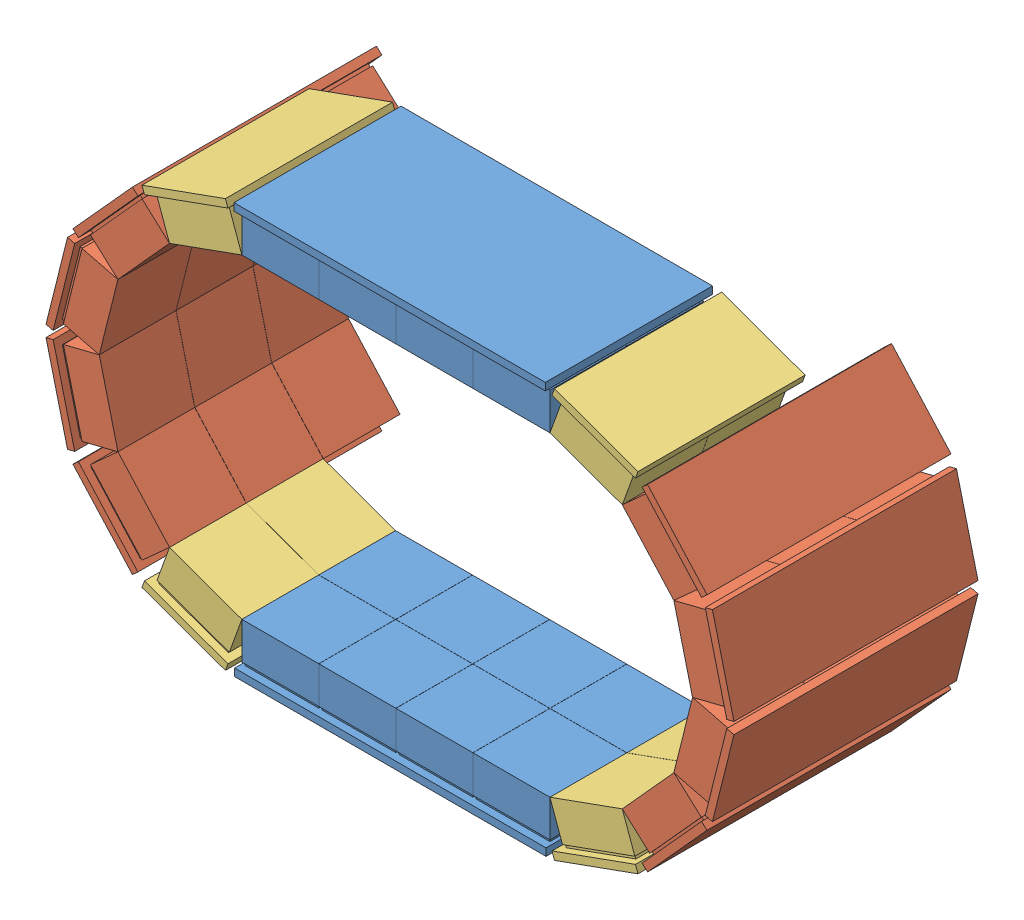
SolidWorks assembly HorseShoes, configuration Default. Lengths in mm.
Overall size (517.67 317.54 165).
16 component instances, 3 part files, 10 mates.
Components (placement in the parent):
- 52mmTOPBOTTOM-1: 52mmTOPBOTTOM [Default] at (-69.8528 -35.4842 8.7442) size (210.55 32 113)
- SideDetector-1: SideDetector [Default] at (215.9367 233.9438 -54.2197) x (-0.242515 0.970148 0) z (0 0 1) size (268 155.36 165)
  - 52mmX4-1: 52mmX4 [Default] at (-99.1405 6.5957 36.9639) size (60 32 165)
  - 52mmX4-2: 52mmX4 [Default] at (-35.1412 22.594 36.9639) x (0.882373 0.47055 0) z (0 0 1) size (60 32 165)
  - 52mmX4-3: 52mmX4 [Default] at (-163.1399 22.594 36.9639) x (0.882373 -0.47055 0) z (0 0 1) size (60 32 165)
  - 52mmX4-4: 52mmX4 [Default] at (-212.0831 66.8254 36.9639) x (0.557166 -0.830401 0) z (0 0 1) size (60 32 165)
  - 52mmX3-1: 52mmX3 [Default] at (-234.4563 128.8843 62.9639) x (0.100883 -0.994898 0) z (0 0 1) size (60 32 113)
  - 52mmX3-2: 52mmX3 [Default] at (13.802 66.8254 62.9639) x (0.557166 0.830401 0) z (0 0 1) size (60 32 113)
- SideDetector-2: SideDetector [Default] at (-199.3424 -27.5859 -54.2197) x (0.242515 -0.970148 0) z (0 0 1) size (268 155.36 165)
  - 52mmX4-1: 52mmX4 [Default] at (-99.1405 6.5957 36.9639) size (60 32 165)
  - 52mmX4-2: 52mmX4 [Default] at (-35.1412 22.594 36.9639) x (0.882373 0.47055 0) z (0 0 1) size (60 32 165)
  - 52mmX4-3: 52mmX4 [Default] at (-163.1399 22.594 36.9639) x (0.882373 -0.47055 0) z (0 0 1) size (60 32 165)
  - 52mmX4-4: 52mmX4 [Default] at (-212.0831 66.8254 36.9639) x (0.557166 -0.830401 0) z (0 0 1) size (60 32 165)
  - 52mmX3-1: 52mmX3 [Default] at (-234.4563 128.8843 62.9639) x (0.100883 -0.994898 0) z (0 0 1) size (60 32 113)
  - 52mmX3-2: 52mmX3 [Default] at (13.802 66.8254 62.9639) x (0.557166 0.830401 0) z (0 0 1) size (60 32 113)
- 52mmTOPBOTTOM-2: 52mmTOPBOTTOM [Default] at (86.4472 241.8421 8.7442) x (-1 0 0) z (0 0 1) size (210.55 32 113)
Mates (geometry in assembly coordinates):
- Coincident1: coincident anti-aligned: line of 52mmTOPBOTTOM-1 through (112.4472 -3.4842 61.2442) axis (0 0 -1); line of SideDetector-1/52mmX3-1 through (112.4472 -3.4842 9.3442) axis (0 0 1)
- Coincident2: coincident: point of 52mmTOPBOTTOM-1; point of SideDetector-1/52mmX3-1
- Parallel1: parallel anti-aligned: line of 52mmTOPBOTTOM-1 through (-43.7528 -3.4842 61.2442) axis (1 0 0); line of 52mmTOPBOTTOM-2 through (8.2472 209.8421 61.2442) axis (-1 0 0)
- Parallel2: parallel anti-aligned: line of 52mmTOPBOTTOM-1 through (-95.8528 -3.4842 9.3442) axis (0 0 1); line of 52mmTOPBOTTOM-2 through (-95.8528 209.8421 61.2442) axis (0 0 -1)
- Coincident5: coincident anti-aligned: line of 52mmTOPBOTTOM-1 through (-95.8528 -3.4842 9.3442) axis (0 0 1); line of SideDetector-2/52mmX3-2 through (-95.8528 -3.4842 61.2442) axis (0 0 -1)
- Coincident6: coincident: point of 52mmTOPBOTTOM-1; point of SideDetector-2/52mmX3-2
- Coincident7: coincident anti-aligned: line of SideDetector-2/52mmX3-1 through (-95.8528 209.8421 9.3442) axis (0 0 1); line of 52mmTOPBOTTOM-2 through (-95.8528 209.8421 61.2442) axis (0 0 -1)
- Coincident8: coincident anti-aligned: line of SideDetector-1/52mmX3-2 through (112.4472 209.8421 61.2442) axis (0 0 -1); line of 52mmTOPBOTTOM-2 through (112.4472 209.8421 9.3442) axis (0 0 1)
- Coincident9: coincident: point of SideDetector-2/52mmX3-1; point of 52mmTOPBOTTOM-2
- Coincident11: coincident anti-aligned: line of 52mmTOPBOTTOM-1 through (-95.8528 -3.4842 61.2442) axis (0 -1 0); line of 52mmTOPBOTTOM-2 through (-95.8528 209.8421 61.2442) axis (0 1 0)
